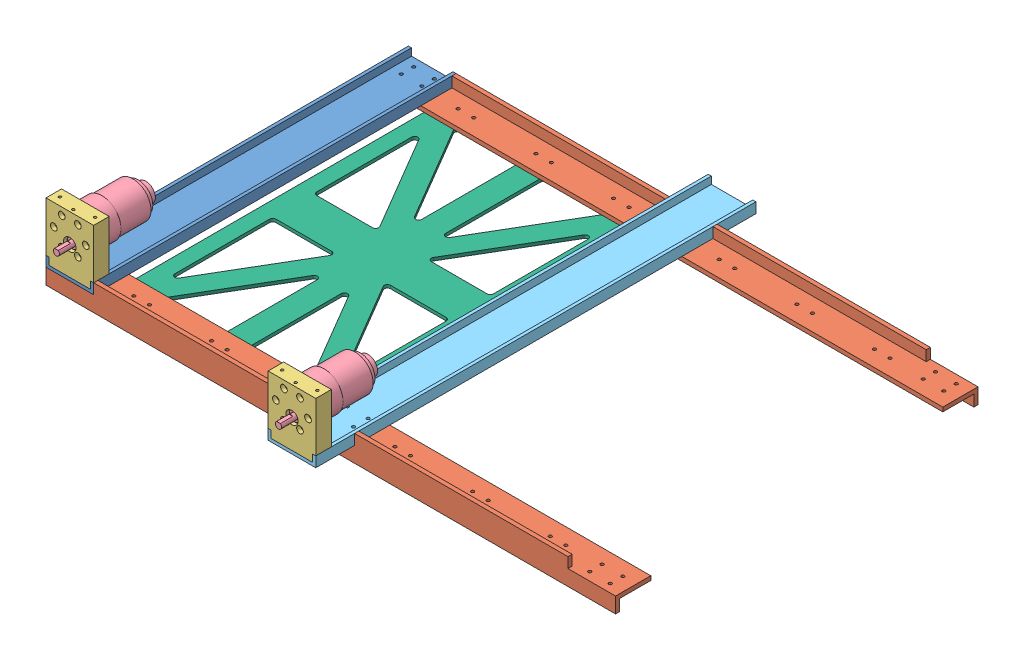
SolidWorks assembly bottom assembly, configuration Default. Lengths in mm.
Overall size (550 73 438).
11 component instances, 6 part files, 18 mates.
Components (placement in the parent):
- bottom crossbar motorholder-1: bottom crossbar motorholder [Default] at (-24.8153 -4.742 -171.2755) size (46 10 350)
- bottom sidebar-1: bottom sidebar [Default] at (-27.8153 -9.3479 176.5956) x (0 0 -1) z (1 0 0) size (34 25 550)
- motor-mount-assembly-1: motor-mount-assembly [Default] at (7.2374 34.1323 154.6369) size (46 55 86.5)
  - mount-1: mount [Default] at (-12.0528 -11.3743 9.0876) size (46 55 15)
  - gearnotor_w_encoder-1: gearnotor_w_encoder [Default] at (-12.0528 -4.3743 -6.9124) size (36.8 36.8 86.5)
- middle crossbar-1: middle crossbar [Default] at (227.1847 -4.742 -208.7755) size (46 10 425)
- bottom sidebar-2: bottom sidebar [Default] at (522.1847 -9.3479 -169.1467) x (0 0 1) z (-1 0 0) size (34 25 550)
- motor-mount-assembly-2: motor-mount-assembly [Default] at (259.2374 34.1323 192.1369) size (46 55 86.5)
  - mount-1: mount [Default] at (-12.0528 -11.3743 9.0876) size (46 55 15)
  - gearnotor_w_encoder-1: gearnotor_w_encoder [Default] at (-12.0528 -4.3743 -6.9124) size (36.8 36.8 86.5)
- bottom support plate-1: bottom support plate [Default] at (121.1847 -14.742 3.7238) x (0 0 1) z (-1 0 0) size (340 3 200)
Mates (geometry in assembly coordinates):
- Coincident1: coincident anti-aligned: plane of bottom crossbar motorholder-1 through (-27.8153 -7.742 178.7245) normal (0 -1 0); plane of bottom sidebar-1 through (522.1847 -7.742 144.7245) normal (0 1 0)
- Concentric3: concentric anti-aligned: cylinder of bottom crossbar motorholder-1 through (-14.8153 -7.742 170.7245) axis (0 -1 0) radius 1.5; cylinder of bottom sidebar-1 through (-14.8153 -7.742 170.7245) axis (0 1 0) radius 1.5
- Concentric5: concentric anti-aligned: cylinder of bottom crossbar motorholder-1 through (5.1847 -7.742 170.7245) axis (0 -1 0) radius 1.5; cylinder of bottom sidebar-1 through (5.1847 -7.742 170.7245) axis (0 1 0) radius 1.5
- Coincident2: coincident aligned: plane of bottom sidebar-1 through (522.1847 2.258 178.7245) normal (0 0 1); plane of motor-mount-assembly-1/mount-1 through (-4.8153 22.758 178.7245) normal (0 0 1)
- Coincident3: coincident anti-aligned: plane of bottom crossbar motorholder-1 through (15.1847 -4.742 178.7245) normal (0 1 0); plane of motor-mount-assembly-1/mount-1 through (-24.8153 -4.742 178.7245) normal (0 -1 0)
- Concentric6: concentric aligned: cylinder of bottom crossbar motorholder-1 through (5.1847 -7.742 170.7245) axis (0 -1 0) radius 1.5; cylinder of motor-mount-assembly-1/mount-1 through (5.1847 -4.742 170.7245) axis (0 -1 0) radius 1.25
- Coincident4: coincident anti-aligned: plane of bottom sidebar-1 through (224.1847 2.258 144.7245) normal (1 0 0); plane of middle crossbar-1 through (224.1847 2.258 216.2245) normal (-1 0 0)
- Coincident5: coincident anti-aligned: plane of bottom sidebar-1 through (522.1847 -7.742 144.7245) normal (0 1 0); plane of middle crossbar-1 through (224.1847 -7.742 216.2245) normal (0 -1 0)
- Concentric8: concentric aligned: cylinder of bottom sidebar-1 through (237.1847 -7.742 152.7245) axis (0 1 0) radius 1.5; cylinder of middle crossbar-1 through (237.1847 -4.742 152.7245) axis (0 1 0) radius 1.5
- Coincident6: coincident anti-aligned: plane of bottom crossbar motorholder-1 through (-27.8153 -7.742 178.7245) normal (0 -1 0); plane of bottom sidebar-2 through (-27.8153 -7.742 -137.2755) normal (0 1 0)
- Concentric9: concentric anti-aligned: cylinder of bottom crossbar motorholder-1 through (-14.8153 -7.742 -163.2755) axis (0 -1 0) radius 1.5; cylinder of bottom sidebar-2 through (-14.8153 -7.742 -163.2755) axis (0 1 0) radius 1.5
- Concentric10: concentric anti-aligned: cylinder of bottom crossbar motorholder-1 through (5.1847 -7.742 -151.2755) axis (0 -1 0) radius 1.5; cylinder of bottom sidebar-2 through (5.1847 -7.742 -151.2755) axis (0 1 0) radius 1.5
- Coincident7: coincident anti-aligned: plane of middle crossbar-1 through (267.1847 -4.742 216.2245) normal (0 1 0); plane of motor-mount-assembly-2/mount-1 through (227.1847 -4.742 216.2245) normal (0 -1 0)
- Coincident8: coincident aligned: plane of middle crossbar-1 through (270.1847 -7.742 216.2245) normal (1 0 0); plane of motor-mount-assembly-2/mount-1 through (270.1847 2.258 201.2245) normal (1 0 0)
- Coincident9: coincident aligned: plane of middle crossbar-1 through (227.1847 -4.742 216.2245) normal (0 0 1); plane of motor-mount-assembly-2/mount-1 through (247.1847 22.758 216.2245) normal (0 0 1)
- Coincident10: coincident anti-aligned: plane of bottom sidebar-1 through (522.1847 -11.742 174.7245) normal (0 -1 0); plane of bottom support plate-1 through (121.0886 -11.742 3.6733) normal (0 1 0)
- Concentric11: concentric aligned: cylinder of bottom sidebar-1 through (38.6847 -7.742 160.2988) axis (0 1 0) radius 1.5; cylinder of bottom support plate-1 through (38.6847 -11.742 160.2988) axis (0 1 0) radius 1.5
- Parallel1: parallel aligned: plane of bottom crossbar motorholder-1 through (-27.8153 2.258 178.7245) normal (-1 0 0); plane of bottom support plate-1 through (21.1847 -11.742 3.7238) normal (-1 0 0)
